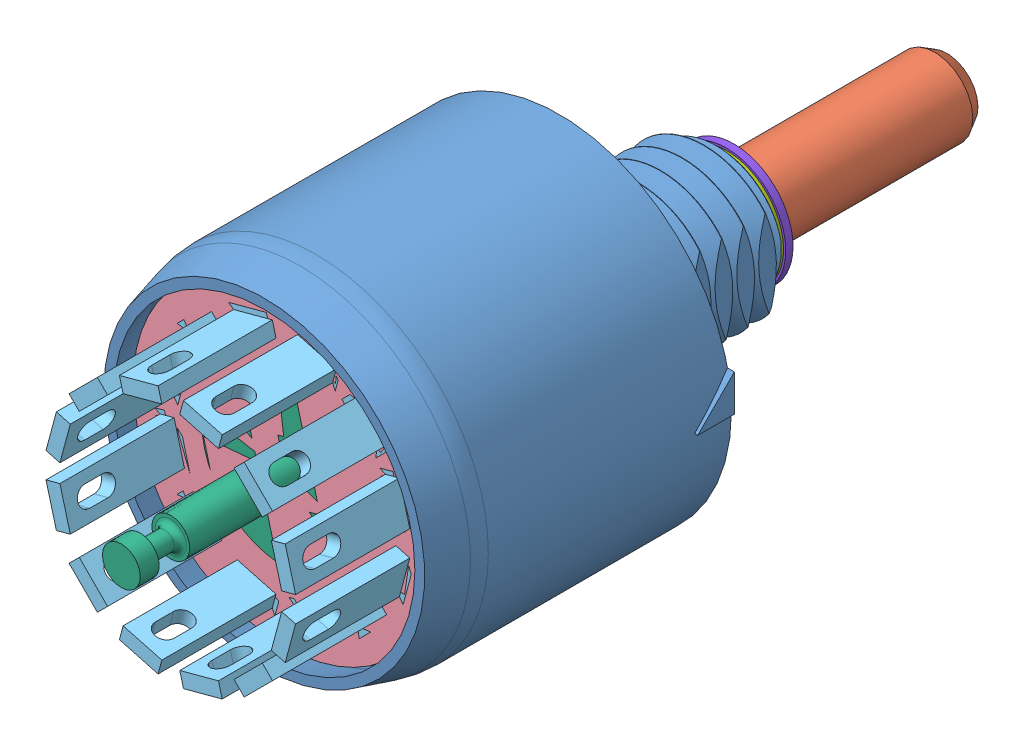
SolidWorks assembly 51M30-01-2-03N, configuration Default. Lengths in mm.
Overall size (16.36 16.36 34.34).
20 component instances, 8 part files, 0 mates.
Components (placement in the parent):
- 58R3008-X-1: 58R3008-X [Default] at origin size (14.45 14.33 19.06)
- 58J2001-1-1: 58J2001-1 [Default] x (0.258819 -0.965926 0) z (0 0 1) size (6.07 7.89 18.87)
- 58Z3130-1: 58Z3130 [Default] at (0 0 1.3207) x (0.258835 -0.965922 0) z (-0.965922 -0.258835 0) size (13.36 6.25 13.36)
- 58ZZ3040-5_ASM-1: 58ZZ3040-5_ASM [Default] at (0 0 7.5691) x (-0.258835 0.965922 0) z (0.965922 0.258835 0) size (13.36 10.5 13.36)
  - 58ZZ3040-X_PLASTIC-1: 58ZZ3040-X_PLASTIC [Default] at origin size (13.36 3.7 13.36)
  - 50C3495-5-B-001-1: 50C3495-5-B-001 [Default] at (-4.2014 0.696 2.4257) x (0.5 0 0.866025) z (0.866025 0 -0.5) size (2 6.75 1.01)
  - 50C3495-5-B-001-2: 50C3495-5-B-001 [Default] at (-2.4257 0.696 4.2014) x (0.866025 0 0.5) z (0.5 0 -0.866025) size (2 6.75 1.01)
  - 50C3495-5-B-001-3: 50C3495-5-B-001 [Default] at (0 0.696 4.8514) x (1 0 0) z (0 0 -1) size (2 6.75 1.01)
  - 50C3495-5-B-001-4: 50C3495-5-B-001 [Default] at (2.4257 0.696 4.2014) x (0.866025 0 -0.5) z (-0.5 0 -0.866025) size (2 6.75 1.01)
  - 50C3495-5-B-001-5: 50C3495-5-B-001 [Default] at (4.2014 0.696 2.4257) x (0.5 0 -0.866025) z (-0.866025 0 -0.5) size (2 6.75 1.01)
  - 50C3495-5-B-001-6: 50C3495-5-B-001 [Default] at (4.8514 0.696 0) x (0 0 -1) z (-1 0 0) size (2 6.75 1.01)
  - 50C3495-5-B-001-7: 50C3495-5-B-001 [Default] at (4.2014 0.696 -2.4257) x (-0.5 0 -0.866025) z (-0.866025 0 0.5) size (2 6.75 1.01)
  - 50C3495-5-B-001-8: 50C3495-5-B-001 [Default] at (2.4257 0.696 -4.2014) x (-0.866025 0 -0.5) z (-0.5 0 0.866025) size (2 6.75 1.01)
  - 50C3495-5-B-001-9: 50C3495-5-B-001 [Default] at (0 0.696 -4.8514) x (-1 0 0) z (0 0 1) size (2 6.75 1.01)
  - 50C3495-5-B-001-10: 50C3495-5-B-001 [Default] at (-2.4257 0.696 -4.2014) x (-0.866025 0 0.5) z (0.5 0 0.866025) size (2 6.75 1.01)
  - 50C3495-5-B-001-11: 50C3495-5-B-001 [Default] at (-4.2014 0.696 -2.4257) x (-0.5 0 0.866025) z (0.866025 0 0.5) size (2 6.75 1.01)
  - 50C3495-5-B-001-12: 50C3495-5-B-001 [Default] at (-4.8514 0.696 0) x (0 0 1) z (1 0 0) size (2 6.75 1.01)
  - 58C3026-10-1: 58C3026-10 [Default] at (0 0.3302 0) size (7.16 8.59 7.16)
- 06J1025-12-1: 06J1025-12 [Default] at (0 0 -8.382) x (-1 0 0) z (0 0 -1) size (4.75 4.75 0.3)
- 58J2427-1: 58J2427 [Default] at (0 0 -8.6868) x (-1 0 0) z (0 0 -1) size (4.93 4.93 0.76)
